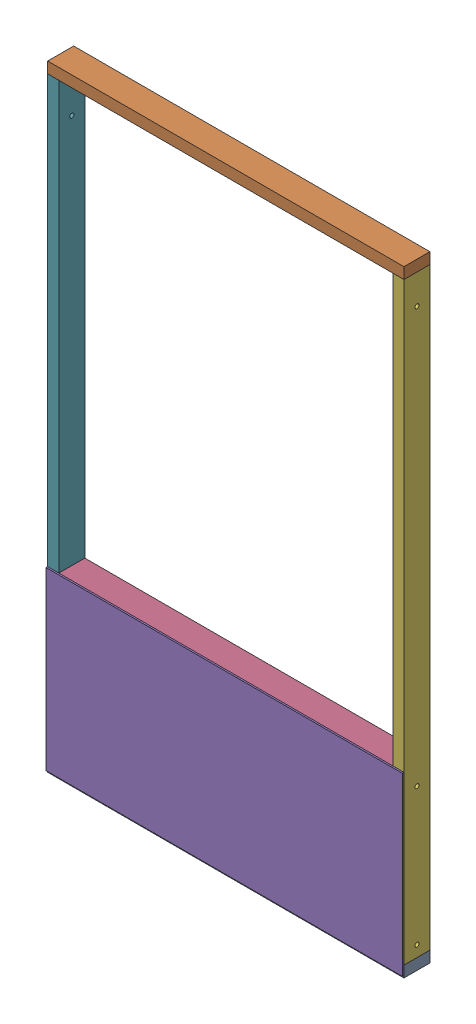
SolidWorks assembly basic panelB, configuration Default. Lengths in mm.
Overall size (1219.2 2108.2 94.46).
7 component instances, 6 part files, 24 mates.
Components (placement in the parent):
- 2x4x48-1: 2x4x48 [Default] x (0 0 -1) z (0 1 0) size (88.9 1219.2 38.1)
- 2x4x48-2: 2x4x48 [Default] at (0 2070.1 0) x (0 0 1) z (0 -1 0) size (88.9 1219.2 38.1)
- 2x4x21-1: 2x4x21 [Default] at (-609.6 552.45 0) x (0 0 -1) z (-1 0 0) size (88.9 533.4 38.1)
- 2x4x45-1: 2x4x45 [Default] at (-38.1 571.5 0) x (0 0 1) z (0 -1 0) size (88.9 1143 38.1)
- plywoodx48x23.7 plywood-1: plywoodx48x23.7 plywood [Default] at (-609.6 289.56 44.45) x (1 0 0) z (0 -1 0) size (1219.2 5.56 601.98)
- 2x4x80-Hole-1: 2x4x80-Hole [Default] at (-19.05 19.05 0) x (0 0 -1) z (1 0 0) size (88.9 2032 38.1)
- 2x4x80-HoleB-1: 2x4x80-HoleB [Default] at (-1200.15 19.05 0) x (0 0 1) z (-1 0 0) size (88.9 2032 38.1)
Mates (geometry in assembly coordinates):
- Coincident10: coincident anti-aligned: plane of 2x4x48-1 through (-1219.2 19.05 44.45) normal (0 1 0); plane of 2x4x21-1 through (-609.6 19.05 0) normal (0 -1 0)
- Coincident11: coincident aligned: plane of 2x4x48-1 through (-1219.2 19.05 44.45) normal (0 0 1); plane of 2x4x21-1 through (-628.65 19.05 44.45) normal (0 0 1)
- Coincident12: coincident anti-aligned: plane of 2x4x21-1 through (-609.6 552.45 0) normal (0 1 0); plane of 2x4x45-1 through (-1181.1 552.45 -44.45) normal (0 -1 0)
- Coincident13: coincident aligned: plane of 2x4x21-1 through (-628.65 19.05 44.45) normal (0 0 1); plane of 2x4x45-1 through (-1181.1 552.45 44.45) normal (0 0 1)
- Coincident18: coincident anti-aligned: plane of 2x4x48-1 through (-1219.2 19.05 44.45) normal (0 1 0); plane of 2x4x80-Hole-2 through (-1200.15 19.05 0) normal (0 -1 0)
- Coincident19: coincident aligned: plane of 2x4x48-1 through (-1219.2 0 0) normal (-1 0 0); plane of 2x4x80-Hole-2 through (-1219.2 2051.05 -44.45) normal (-1 0 0)
- Coincident20: coincident aligned: plane of 2x4x48-1 through (-1219.2 19.05 -44.45) normal (0 0 -1); plane of 2x4x80-Hole-2 through (-1219.2 2051.05 -44.45) normal (0 0 -1)
- Coincident21: coincident anti-aligned: plane of 2x4x48-1 through (-1219.2 19.05 44.45) normal (0 1 0); plane of 2x4x80-Hole-1 through (-19.05 19.05 0) normal (0 -1 0)
- Coincident22: coincident aligned: plane of 2x4x48-1 through (0 0 0) normal (1 0 0); plane of 2x4x80-Hole-1 through (0 2051.05 44.45) normal (1 0 0)
- Coincident23: coincident anti-aligned: plane of plywoodx48x23.7 plywood-1 through (-609.6 289.56 44.45) normal (0 0 -1); plane of 2x4x80-Hole-1 through (0 2051.05 44.45) normal (0 0 1)
- Coincident24: coincident aligned: plane of 2x4x48-1 through (-1219.2 19.05 -44.45) normal (0 0 -1); plane of 2x4x80-Hole-1 through (0 2051.05 -44.45) normal (0 0 -1)
- Coincident25: coincident aligned: plane of plywoodx48x23.7 plywood-1 through (0 -11.43 50.0063) normal (1 0 0); plane of 2x4x80-Hole-1 through (0 2051.05 44.45) normal (1 0 0)
- Coincident26: coincident anti-aligned: plane of 2x4x45-1 through (-38.1 571.5 0) normal (1 0 0); plane of 2x4x80-Hole-1 through (-38.1 2051.05 44.45) normal (-1 0 0)
- Symmetric1: symmetric aligned: plane of 2x4x48-1 through (0 0 0) normal (1 0 0); plane of 2x4x21-1 through (-1219.2 0 0) normal (-1 0 0); plane of 2x4x48-1 through (-609.6 552.45 0) normal (-1 0 0)
- Coincident27: coincident anti-aligned: plane of 2x4x48-2 through (-1219.2 2051.05 -44.45) normal (0 -1 0); plane of 2x4x80-Hole-2 through (-1200.15 2051.05 0) normal (0 1 0)
- Coincident28: coincident aligned: plane of 2x4x48-2 through (-1219.2 2051.05 -44.45) normal (0 0 -1); plane of 2x4x80-Hole-2 through (-1219.2 2051.05 -44.45) normal (0 0 -1)
- Coincident29: coincident aligned: plane of 2x4x48-2 through (-1219.2 2070.1 0) normal (-1 0 0); plane of 2x4x80-Hole-2 through (-1219.2 2051.05 -44.45) normal (-1 0 0)
- Coincident30: coincident anti-aligned: plane of 2x4x48-2 through (-1219.2 2051.05 -44.45) normal (0 -1 0); plane of 2x4x80-HoleB-1 through (-1200.15 2051.05 0) normal (0 1 0)
- Coincident32: coincident aligned: plane of 2x4x48-2 through (-1219.2 2051.05 -44.45) normal (0 0 -1); plane of 2x4x80-HoleB-1 through (-1219.2 2051.05 -44.45) normal (0 0 -1)
- Coincident33: coincident aligned: plane of 2x4x48-2 through (-1219.2 2051.05 -44.45) normal (0 0 -1); plane of 2x4x80-Hole-1 through (0 2051.05 -44.45) normal (0 0 -1)
- Coincident34: coincident: line of 2x4x48-2 through (-1219.2 2051.05 -44.45) axis (1 0 0); plane of 2x4x80-Hole-1 through (-19.05 2051.05 0) normal (0 1 0)
- Coincident35: coincident aligned: plane of 2x4x48-2 through (0 2070.1 0) normal (1 0 0); plane of 2x4x80-Hole-1 through (0 2051.05 44.45) normal (1 0 0)
- Coincident36: coincident aligned: plane of 2x4x48-2 through (-1219.2 2070.1 0) normal (-1 0 0); plane of 2x4x80-HoleB-1 through (-1219.2 2051.05 -44.45) normal (-1 0 0)
- Distance1: distance = 7.62 mm aligned: plane of 2x4x48-1 through (-1219.2 -19.05 44.45) normal (0 -1 0); plane of plywoodx48x23.7 plywood-1 through (-1219.2 -11.43 50.0063) normal (0 -1 0)
